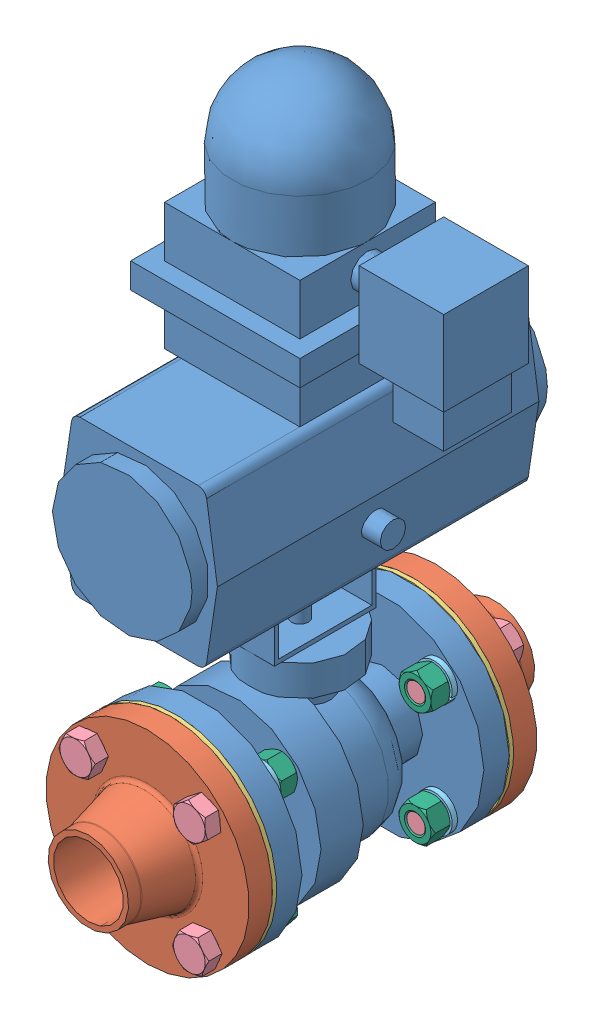
SolidWorks assembly 2incontrolvalve, configuration Default. Lengths in mm.
Overall size (215.9 528.64 347.98).
29 component instances, 6 part files, 21 mates.
Components (placement in the parent):
- 2in-ec-valve-1: 2in-ec-valve [P274] at origin size (215.9 528.64 266.7)
- 2inweldneckflange-1: 2inweldneckflange [2.00 RF] at (0 -201.6125 96.8375) x (1 0 0) z (0 -1 0) size (152.4 75.09 152.4)
- 2inweldneckflange-2: 2inweldneckflange [2.00 RF] at (0 -201.6125 -84.1375) x (1 0 0) z (0 1 0) size (152.4 75.09 152.4)
- 2ingasket-2: 2ingasket [Default] at (0 0 93.6625) size (152.4 152.4 3.17)
- 2ingasket-3: 2ingasket [Default] at (0 0 -84.1375) size (152.4 152.4 3.17)
- hfbolt 0.625-18x2.25x2.25-n-1: hfbolt 0.625-18x2.25x2.25-n [Default] at (42.6562 -244.2687 125.5776) x (0 0 -1) z (0.923783 -0.382918 0) size (68.43 27.51 23.83)
- hfbolt 0.625-18x2.25x2.25-n-2: hfbolt 0.625-18x2.25x2.25-n [Default] at (42.6562 -158.9563 -112.8776) x (0 0 1) z (0.706648 0.707566 0) size (68.43 27.51 23.83)
- lw 0.625-5: lw 0.625 [Default] at (42.6562 -244.2687 74.6125) x (0 0 1) z (0.706648 0.707566 0) size (3.96 27.41 27.36)
- lw 0.625-6: lw 0.625 [Default] at (42.6562 -158.9563 -61.9125) x (0 0 -1) z (0.923783 -0.382918 0) size (3.96 27.41 27.36)
- hnut 0.6250-11-d-n-5: hnut 0.6250-11-d-n [Default] at (42.6562 -244.2687 56.4515) x (0.923728 0.383049 0) z (0 0 -1) size (23.83 27.51 14.2)
- hnut 0.6250-11-d-n-6: hnut 0.6250-11-d-n [Default] at (42.6562 -158.9563 -43.7515) size (23.83 27.51 14.2)
- hnut 0.6250-11-d-n-7: hnut 0.6250-11-d-n [Default] at (-42.6562 -244.2687 56.4515) x (0.383049 -0.923728 0) z (0 0 -1) size (23.83 27.51 14.2)
- hnut 0.6250-11-d-n-8: hnut 0.6250-11-d-n [Default] at (-42.6562 -158.9563 56.4515) x (-0.923728 -0.383049 0) z (0 0 -1) size (23.83 27.51 14.2)
- hnut 0.6250-11-d-n-9: hnut 0.6250-11-d-n [Default] at (42.6562 -158.9563 56.4515) x (-0.383049 0.923728 0) z (0 0 -1) size (23.83 27.51 14.2)
- lw 0.625-7: lw 0.625 [Default] at (-42.6562 -244.2687 74.6125) x (0 0 1) z (0.707566 -0.706648 0) size (3.96 27.41 27.36)
- lw 0.625-8: lw 0.625 [Default] at (-42.6562 -158.9563 74.6125) x (0 0 1) z (-0.706648 -0.707566 0) size (3.96 27.41 27.36)
- lw 0.625-9: lw 0.625 [Default] at (42.6562 -158.9563 74.6125) x (0 0 1) z (-0.707566 0.706648 0) size (3.96 27.41 27.36)
- hfbolt 0.625-18x2.25x2.25-n-3: hfbolt 0.625-18x2.25x2.25-n [Default] at (-42.6562 -244.2687 125.5776) x (0 0 -1) z (-0.382918 -0.923783 0) size (68.43 27.51 23.83)
- hfbolt 0.625-18x2.25x2.25-n-4: hfbolt 0.625-18x2.25x2.25-n [Default] at (-42.6562 -158.9563 125.5776) x (0 0 -1) z (-0.923783 0.382918 0) size (68.43 27.51 23.83)
- hfbolt 0.625-18x2.25x2.25-n-5: hfbolt 0.625-18x2.25x2.25-n [Default] at (42.6562 -158.9563 125.5776) x (0 0 -1) z (0.382918 0.923783 0) size (68.43 27.51 23.83)
- hnut 0.6250-11-d-n-10: hnut 0.6250-11-d-n [Default] at (-42.6562 -158.9563 -43.7515) x (0 1 0) z (0 0 1) size (23.83 27.51 14.2)
- hnut 0.6250-11-d-n-11: hnut 0.6250-11-d-n [Default] at (-42.6562 -244.2687 -43.7515) x (-1 0 0) z (0 0 1) size (23.83 27.51 14.2)
- hnut 0.6250-11-d-n-12: hnut 0.6250-11-d-n [Default] at (42.6562 -244.2687 -43.7515) x (0 -1 0) z (0 0 1) size (23.83 27.51 14.2)
- lw 0.625-10: lw 0.625 [Default] at (-42.6562 -158.9563 -61.9125) x (0 0 -1) z (0.382918 0.923783 0) size (3.96 27.41 27.36)
- lw 0.625-11: lw 0.625 [Default] at (-42.6562 -244.2687 -61.9125) x (0 0 -1) z (-0.923783 0.382918 0) size (3.96 27.41 27.36)
- lw 0.625-12: lw 0.625 [Default] at (42.6562 -244.2687 -61.9125) x (0 0 -1) z (-0.382918 -0.923783 0) size (3.96 27.41 27.36)
- hfbolt 0.625-18x2.25x2.25-n-6: hfbolt 0.625-18x2.25x2.25-n [Default] at (-42.6562 -158.9563 -112.8776) x (0 0 1) z (-0.707566 0.706648 0) size (68.43 27.51 23.83)
- hfbolt 0.625-18x2.25x2.25-n-7: hfbolt 0.625-18x2.25x2.25-n [Default] at (-42.6562 -244.2687 -112.8776) x (0 0 1) z (-0.706648 -0.707566 0) size (68.43 27.51 23.83)
- hfbolt 0.625-18x2.25x2.25-n-8: hfbolt 0.625-18x2.25x2.25-n [Default] at (42.6562 -244.2687 -112.8776) x (0 0 1) z (0.707566 -0.706648 0) size (68.43 27.51 23.83)
Mates (geometry in assembly coordinates):
- Concentric1: concentric aligned: cylinder of 2in-ec-valve-1 through (0 -201.6125 133.35) axis (0 0 -1) radius 25.4; cylinder of 2inweldneckflange-1 through (0 -201.6125 96.8375) axis (0 0 -1) radius 26.2509
- Coincident2: coincident anti-aligned: plane of 2in-ec-valve-1 through (0 -201.6125 95.25) normal (0 0 1); plane of 2inweldneckflange-1 through (26.2509 -201.6125 95.25) normal (0 0 -1)
- Concentric2: concentric anti-aligned: cylinder of 2in-ec-valve-1 through (0 -201.6125 133.35) axis (0 0 -1) radius 25.4; cylinder of 2inweldneckflange-2 through (0 -201.6125 -84.1375) axis (0 0 1) radius 26.2509
- Coincident3: coincident anti-aligned: plane of 2in-ec-valve-1 through (0 -201.6125 -82.55) normal (0 0 -1); plane of 2inweldneckflange-2 through (26.2509 -201.6125 -82.55) normal (0 0 1)
- Inplace1: in place: moOrthogonalPlaneRef_w of 2in-ec-valve-1 through (0 -201.6125 93.6625) normal (0 0 1); unknown of 2ingasket-2
- Coincident4: coincident aligned: plane of ?; plane of ?
- Coincident5: coincident aligned: moOrthogonalPlaneRef_w of 2in-ec-valve-1 through (0 0 93.6625) axis (0 1 0); plane of 2ingasket-2 through (0 0 93.6625) normal (0 1 0)
- Coincident6: coincident anti-aligned: moOrthogonalPlaneRef_w of 2in-ec-valve-1 through (0 0 93.6625) axis (-1 0 0); plane of 2ingasket-2 through (0 0 93.6625) normal (1 0 0)
- Coincident7: coincident anti-aligned: plane of 2in-ec-valve-1 through (0 -201.6125 -80.9625) normal (0 0 -1); plane of 2ingasket-3 through (0 -201.6125 -80.9625) normal (0 0 1)
- Concentric9: concentric aligned: cylinder of 2inweldneckflange-1 through (42.6562 -244.2687 95.25) axis (0 0 1) radius 9.525; cylinder of hfbolt 0.625-18x2.25x2.25-n-1 through (42.6562 -244.2687 125.5776) axis (0 0 1) radius 11.9126
- Coincident14: coincident anti-aligned: plane of 2inweldneckflange-1 through (76.2 -201.6125 114.3) normal (0 0 1); plane of hfbolt 0.625-18x2.25x2.25-n-1 through (47.9234 -231.5616 114.3) normal (0 0 -1)
- Concentric10: concentric aligned: cylinder of 2inweldneckflange-2 through (42.6562 -158.9563 -82.55) axis (0 0 -1) radius 9.525; cylinder of hfbolt 0.625-18x2.25x2.25-n-2 through (42.6562 -158.9563 -112.8776) axis (0 0 -1) radius 11.9126
- Coincident15: coincident anti-aligned: plane of 2inweldneckflange-2 through (76.2 -201.6125 -101.6) normal (0 0 -1); plane of hfbolt 0.625-18x2.25x2.25-n-2 through (52.3891 -168.6766 -101.6) normal (0 0 1)
- Concentric11: concentric anti-aligned: cylinder of 2in-ec-valve-1 through (42.6562 -244.2687 47.6717) axis (0 0 1) radius 9.525; cylinder of lw 0.625-5 through (42.6562 -244.2687 39.6875) axis (0 0 -1) radius 8.2169
- Coincident16: coincident anti-aligned: plane of 2in-ec-valve-1 through (0 -201.6125 74.6125) normal (0 0 -1); plane of lw 0.625-5 through (48.4702 -250.0752 74.6125) normal (0 0 1)
- Concentric12: concentric anti-aligned: cylinder of 2in-ec-valve-1 through (42.6562 -158.9563 -34.9717) axis (0 0 -1) radius 9.525; cylinder of lw 0.625-6 through (42.6562 -158.9563 -26.9875) axis (0 0 1) radius 8.2169
- Coincident17: coincident anti-aligned: plane of 2in-ec-valve-1 through (0 -201.6125 -61.9125) normal (0 0 1); plane of lw 0.625-6 through (45.8026 -151.3657 -61.9125) normal (0 0 -1)
- Concentric13: concentric aligned: cylinder of lw 0.625-5 through (42.6562 -244.2687 39.6875) axis (0 0 -1) radius 13.7033; cylinder of hnut 0.6250-11-d-n-5 through (42.6562 -244.2687 81.489) axis (0 0 -1) radius 7.9375
- Coincident18: coincident anti-aligned: plane of lw 0.625-5 through (52.3522 -253.9521 70.6501) normal (0 0 -1); plane of hnut 0.6250-11-d-n-5 through (47.9252 -256.975 70.6501) normal (0 0 1)
- Concentric14: concentric aligned: cylinder of lw 0.625-6 through (42.6562 -158.9563 -26.9875) axis (0 0 1) radius 13.7033; cylinder of hnut 0.6250-11-d-n-6 through (42.6562 -158.9563 -68.789) axis (0 0 1) radius 7.9375
- Coincident19: coincident anti-aligned: plane of lw 0.625-6 through (47.9035 -146.2974 -57.9501) normal (0 0 1); plane of hnut 0.6250-11-d-n-6 through (42.6562 -145.2008 -57.9501) normal (0 0 -1)
